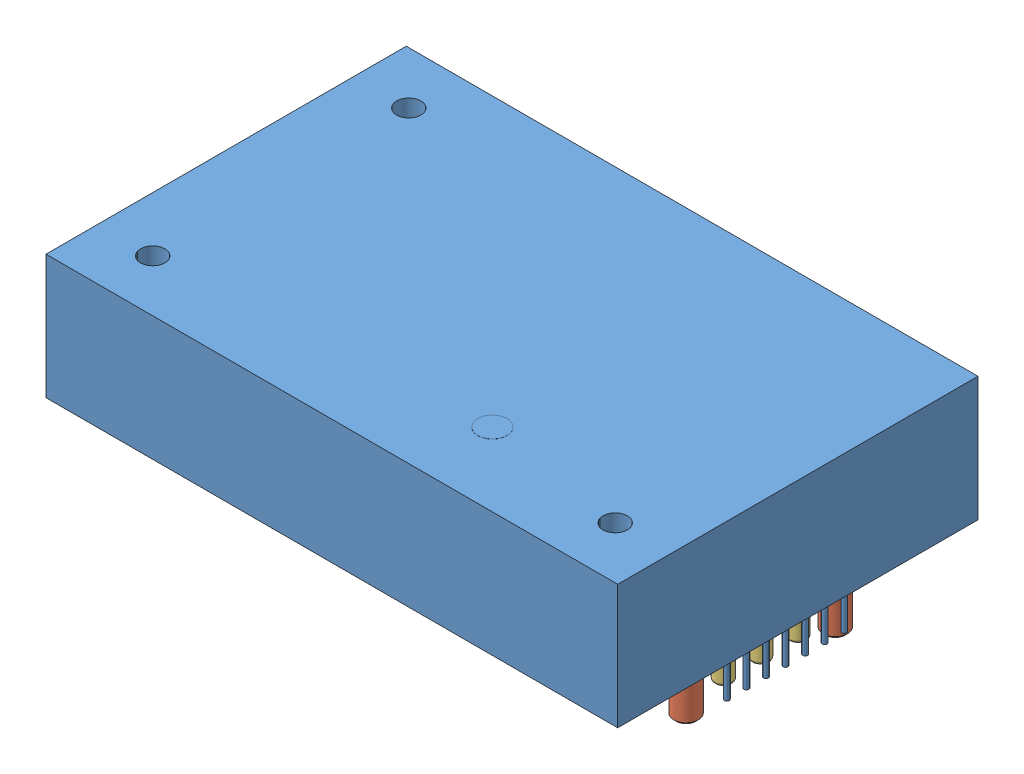
SolidWorks assembly Q48SC12050_w_pins, configuration Default. Lengths in mm.
Overall size (58.4 18.93 36.8).
10 component instances, 3 part files, 18 mates.
Components (placement in the parent):
- Q48SC12050-1: Q48SC12050 [Default] at origin size (58.4 17.01 36.8)
- 0364-0-15-15-13-27-10-0-1: 0364-0-15-15-13-27-10-0 [Default] at (25.4 -3.515 7.62) size (3.05 5.41 3.05)
- 9353-0-15-15-18-27-10-0-1: 9353-0-15-15-18-27-10-0 [Default] at (-25.4 -2.794 7.62) x (0.915791 0 0.401656) z (-0.401656 0 0.915791) size (2.29 4.32 2.29)
- 9353-0-15-15-18-27-10-0-2: 9353-0-15-15-18-27-10-0 [Default] at (-25.4 -2.794 3.81) size (2.29 4.32 2.29)
- 9353-0-15-15-18-27-10-0-3: 9353-0-15-15-18-27-10-0 [Default] at (-25.4 -2.794 0) size (2.29 4.32 2.29)
- 9353-0-15-15-18-27-10-0-4: 9353-0-15-15-18-27-10-0 [Default] at (-25.4 -2.794 -7.62) size (2.29 4.32 2.29)
- 0364-0-15-15-13-27-10-0-2: 0364-0-15-15-13-27-10-0 [Default] at (25.4 -3.515 -7.62) x (0.998442 0 -0.055796) z (0.055796 0 0.998442) size (3.05 5.41 3.05)
- 9353-0-15-15-18-27-10-0-5: 9353-0-15-15-18-27-10-0 [Default] at (25.4 -2.794 3.81) size (2.29 4.32 2.29)
- 9353-0-15-15-18-27-10-0-6: 9353-0-15-15-18-27-10-0 [Default] at (25.4 -2.794 0) size (2.29 4.32 2.29)
- 9353-0-15-15-18-27-10-0-7: 9353-0-15-15-18-27-10-0 [Default] at (25.4 -2.794 -3.81) size (2.29 4.32 2.29)
Mates (geometry in assembly coordinates):
- Concentric1: concentric aligned: cylinder of Q48SC12050-1 through (-25.4 -4.3 7.62) axis (0 1 0) radius 0.5; cylinder of 9353-0-15-15-18-27-10-0-1 through (-25.4 -0.635 7.62) axis (0 1 0) radius 0.8763
- Concentric2: concentric aligned: cylinder of Q48SC12050-1 through (-25.4 -4.3 3.81) axis (0 1 0) radius 0.5; cylinder of 9353-0-15-15-18-27-10-0-2 through (-25.4 -0.635 3.81) axis (0 1 0) radius 0.8763
- Concentric3: concentric aligned: cylinder of Q48SC12050-1 through (-25.4 -4.3 0) axis (0 1 0) radius 0.5; cylinder of 9353-0-15-15-18-27-10-0-3 through (-25.4 -0.635 0) axis (0 1 0) radius 0.8763
- Concentric4: concentric aligned: cylinder of Q48SC12050-1 through (-25.4 -4.3 -7.62) axis (0 1 0) radius 0.5; cylinder of 9353-0-15-15-18-27-10-0-4 through (-25.4 -0.635 -7.62) axis (0 1 0) radius 0.8763
- Coincident3: coincident aligned: plane of 9353-0-15-15-18-27-10-0-1 through (-25.4 -0.635 7.62) normal (0 1 0); plane of 9353-0-15-15-18-27-10-0-2 through (-25.4 -0.635 3.81) normal (0 1 0)
- Coincident4: coincident aligned: plane of 9353-0-15-15-18-27-10-0-2 through (-25.4 -0.635 3.81) normal (0 1 0); plane of 9353-0-15-15-18-27-10-0-3 through (-25.4 -0.635 0) normal (0 1 0)
- Coincident5: coincident aligned: plane of 9353-0-15-15-18-27-10-0-3 through (-25.4 -0.635 0) normal (0 1 0); plane of 9353-0-15-15-18-27-10-0-4 through (-25.4 -0.635 -7.62) normal (0 1 0)
- Concentric5: concentric anti-aligned: cylinder of Q48SC12050-1 through (25.4 -4.3 7.62) axis (0 1 0) radius 0.75; cylinder of 0364-0-15-15-13-27-10-0-1 through (25.4 -3.515 7.62) axis (0 -1 0) radius 1.245
- Concentric6: concentric anti-aligned: cylinder of Q48SC12050-1 through (25.4 -4.3 -7.62) axis (0 1 0) radius 0.75; cylinder of 0364-0-15-15-13-27-10-0-2 through (25.4 -3.515 -7.62) axis (0 -1 0) radius 1.245
- Concentric7: concentric aligned: cylinder of Q48SC12050-1 through (25.4 -4.3 -3.81) axis (0 1 0) radius 0.5; cylinder of 9353-0-15-15-18-27-10-0-7 through (25.4 -0.635 -3.81) axis (0 1 0) radius 0.8763
- Concentric8: concentric aligned: cylinder of Q48SC12050-1 through (25.4 -4.3 0) axis (0 1 0) radius 0.5; cylinder of 9353-0-15-15-18-27-10-0-6 through (25.4 -0.635 0) axis (0 1 0) radius 0.8763
- Concentric9: concentric aligned: cylinder of Q48SC12050-1 through (25.4 -4.3 3.81) axis (0 1 0) radius 0.5; cylinder of 9353-0-15-15-18-27-10-0-5 through (25.4 -0.635 3.81) axis (0 1 0) radius 0.8763
- Coincident6: coincident aligned: plane of 9353-0-15-15-18-27-10-0-5 through (25.4 -0.635 3.81) normal (0 1 0); plane of 9353-0-15-15-18-27-10-0-6 through (25.4 -0.635 0) normal (0 1 0)
- Coincident7: coincident aligned: plane of 9353-0-15-15-18-27-10-0-6 through (25.4 -0.635 0) normal (0 1 0); plane of 9353-0-15-15-18-27-10-0-7 through (25.4 -0.635 -3.81) normal (0 1 0)
- Coincident8: coincident aligned: plane of 0364-0-15-15-13-27-10-0-1 through (25.4 -1.27 6.095) normal (0 -1 0); plane of 0364-0-15-15-13-27-10-0-2 through (25.3149 -1.27 -9.1426) normal (0 -1 0)
- Coincident9: coincident anti-aligned: plane of 0364-0-15-15-13-27-10-0-2 through (25.3149 -1.27 -9.1426) normal (0 -1 0); circle of 9353-0-15-15-18-27-10-0-7
- Coincident10: coincident anti-aligned: circle of 9353-0-15-15-18-27-10-0-4; plane of 0364-0-15-15-13-27-10-0-2 through (25.3149 -1.27 -9.1426) normal (0 -1 0)
- Distance1: distance = 0.635 mm anti-aligned: plane of Q48SC12050-1 through (0 0 0) normal (0 -1 0); plane of 9353-0-15-15-18-27-10-0-2 through (-25.4 -0.635 3.81) normal (0 1 0)
